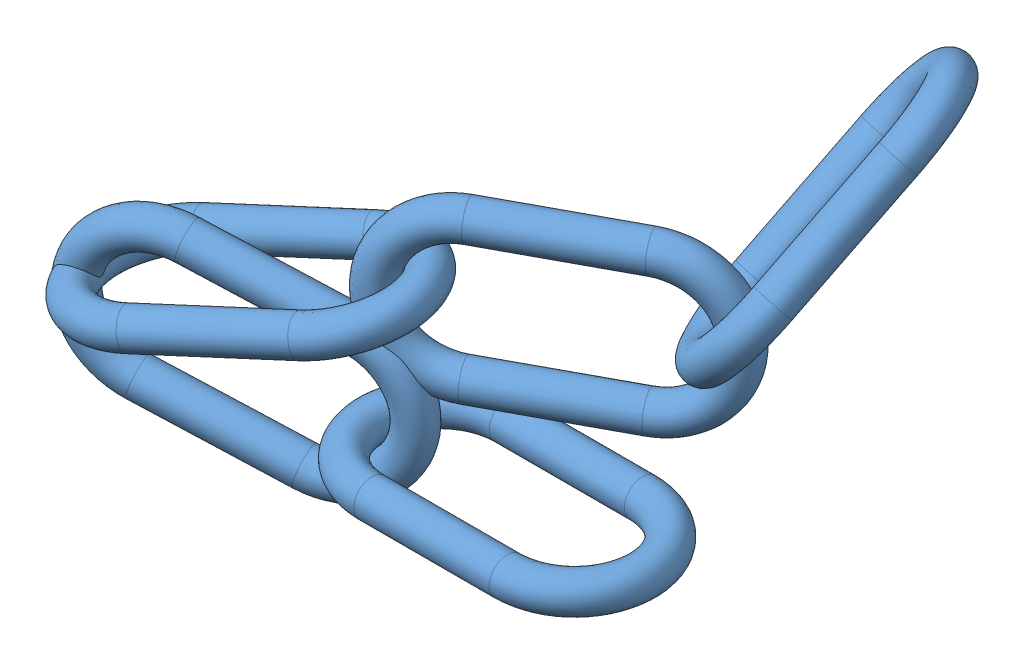
SolidWorks assembly Chain Links, configuration Default. Lengths in mm.
Overall size (67.18 47.95 60.95).
5 component instances, 1 part files, 8 mates.
Components (placement in the parent):
- Link2-1: Link2 [Default] at (-43.0067 7.645 36.555) size (34 4 19)
- Link2-2: Link2 [Default] at (-71.2479 1.1502 29.046) x (0.90302 -0.281037 -0.32492) z (0.26444 0.959697 -0.095149) size (34 4 19)
- Link2-3: Link2 [Default] at (-136.4787 9.7722 53.4374) x (-0.903639 -0.224133 0.364966) z (-0.372688 -0.008405 -0.927919) size (34 4 19)
- Link2-4: Link2 [Default] at (-112.3111 20.9748 46.7204) x (-0.874517 0.008452 0.48492) z (0.010517 -0.999283 0.036384) size (34 4 19)
- Link2-5: Link2 [Default] at (-73.5156 5.7512 40.1554) x (-0.179673 -0.640779 0.746405) z (-0.692436 -0.456568 -0.55864) size (34 4 19)
Mates (geometry in assembly coordinates):
- Perpendicular1: perpendicular: line of Link2-1 through (-94.1169 9.645 36.555) axis (0 -1 0); line of Link2-2 through (-90.988 7.083 34.0233) axis (0.338565 0 0.940943)
- Coincident2: coincident: point of Link2-1; point of Link2-2
- Perpendicular2: perpendicular: line of Link2-2 through (-118.0786 15.5141 43.7709) axis (0.338565 0 0.940943); line of Link2-3 through (-117.8248 16.4528 45.8847) axis (0.211045 -0.974522 -0.075937)
- Coincident4: coincident: point of Link2-2; point of Link2-3
- Perpendicular3: perpendicular: line of Link2-3 through (-90.7156 23.1768 34.9357) axis (0.211045 -0.974522 -0.075937); line of Link2-4 through (-94.8196 20.7225 34.736) axis (0.48488 0.036918 0.873801)
- Coincident6: coincident: point of Link2-3; point of Link2-4
- Perpendicular4: perpendicular: line of Link2-4 through (-68.5841 20.469 20.1884) axis (0.48488 0.036918 0.873801); line of Link2-5 through (-71.1202 20.5126 25.122) axis (0.698749 -0.61721 -0.361665)
- Coincident8: coincident: point of Link2-4; point of Link2-5
